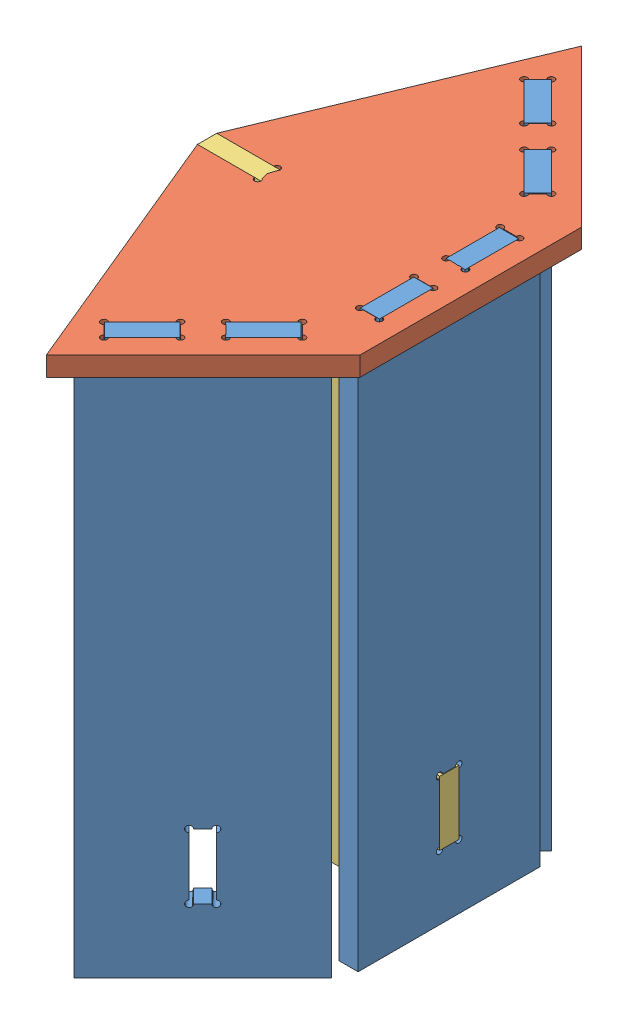
SolidWorks assembly ChairASSLY, configuration Default. Lengths in mm.
Overall size (246.27 518 500).
5 component instances, 3 part files, 13 mates.
Components (placement in the parent):
- Part1-1: Part1 [Default] at (991.7789 -819.0131 -319.6373) size (18 518 170)
- Part5-1: Part5 [Default] at (12065.9695 -301.0131 1743.1464) size (246.27 18 500)
- Part1-2: Part1 [Default] at (869.4047 -819.0131 -194.6999) x (0.707107 0 0.707107) z (-0.707107 0 0.707107) size (18 518 170)
- Part1-3: Part1 [Default] at (989.6128 -819.0131 -494.8667) x (0.707107 0 -0.707107) z (0.707107 0 0.707107) size (18 518 170)
- Stiffener-1: Stiffener [Default] at (-1537.8643 -62.9023 94.9374) size (226.27 518 18)
Mates (geometry in assembly coordinates):
- Width2: width aligned: plane of Part5-1 through (919.0789 -319.0131 -244.3741) normal (-0.707107 0 0.707107); plane of Part5-1 through (883.37 -319.0131 -208.6652) normal (0.707107 0 -0.707107); plane of Part1-2 through (883.5468 -301.0131 -208.842) normal (-0.707107 0 0.707107); plane of Part1-2 through (918.9022 -301.0131 -244.1973) normal (0.707107 0 -0.707107)
- Width3: width aligned: plane of Part1-2 through (882.1326 -819.0131 -181.9719) normal (0.707107 0 0.707107); plane of Part1-2 through (869.4047 -819.0131 -194.6999) normal (-0.707107 0 -0.707107); plane of Part5-1 through (976.001 -319.0131 -301.2962) normal (0.707107 0 0.707107); plane of Part5-1 through (988.729 -319.0131 -288.5683) normal (-0.707107 0 -0.707107)
- Width4: width anti-aligned: plane of Part5-1 through (919.0789 -319.0131 -244.3741) normal (-0.707107 0 0.707107); plane of Part5-1 through (883.37 -319.0131 -208.6652) normal (0.707107 0 -0.707107); plane of Part1-2 through (918.9022 -301.0131 -244.1973) normal (0.707107 0 -0.707107); plane of Part1-2 through (883.5468 -301.0131 -208.842) normal (-0.707107 0 0.707107)
- Coincident16: coincident anti-aligned: plane of Part5-1 through (12065.9695 -319.0131 1743.1464) normal (0 -1 0); plane of Part1-2 through (1002.3408 -319.0131 -302.1801) normal (0 1 0)
- Width5: width anti-aligned: plane of Part5-1 through (991.7789 -319.0131 -339.3873) normal (0 0 -1); plane of Part5-1 through (991.7789 -319.0131 -389.8873) normal (0 0 1); plane of Part1-1 through (991.7789 -301.0131 -339.6373) normal (0 0 1); plane of Part1-1 through (991.7789 -301.0131 -389.6373) normal (0 0 -1)
- Coincident17: coincident anti-aligned: plane of Part1-1 through (1009.7789 -319.0131 -489.6373) normal (0 1 0); plane of Part5-1 through (12065.9695 -319.0131 1743.1464) normal (0 -1 0)
- Width6: width anti-aligned: plane of Part5-1 through (991.7789 -319.0131 -339.3873) normal (1 0 0); plane of Part5-1 through (1009.7789 -319.0131 -339.3873) normal (-1 0 0); plane of Part1-1 through (991.7789 -819.0131 -319.6373) normal (-1 0 0); plane of Part1-1 through (1009.7789 -819.0131 -319.6373) normal (1 0 0)
- Width7: width aligned: plane of Part5-1 through (976.001 -319.0131 -508.4785) normal (0.707107 0 -0.707107); plane of Part5-1 through (988.729 -319.0131 -521.2064) normal (-0.707107 0 0.707107); plane of Part1-3 through (1002.3408 -819.0131 -507.5946) normal (0.707107 0 -0.707107); plane of Part1-3 through (989.6128 -819.0131 -494.8667) normal (-0.707107 0 0.707107)
- Width8: width anti-aligned: plane of Part5-1 through (883.37 -319.0131 -601.1095) normal (0.707107 0 0.707107); plane of Part5-1 through (919.0789 -319.0131 -565.4006) normal (-0.707107 0 -0.707107); plane of Part1-3 through (883.5468 -301.0131 -600.9327) normal (-0.707107 0 -0.707107); plane of Part1-3 through (918.9022 -301.0131 -565.5774) normal (0.707107 0 0.707107)
- Coincident18: coincident anti-aligned: plane of Part5-1 through (12065.9695 -319.0131 1743.1464) normal (0 -1 0); plane of Part1-3 through (882.1326 -319.0131 -627.8028) normal (0 1 0)
- Width9: width anti-aligned: plane of Stiffener-1 through (-1537.8643 -62.9023 -413.8873) normal (0 0 -1); plane of Stiffener-1 through (-1537.8643 -62.9023 -395.8873) normal (0 0 1); plane of Part5-1 through (783.5068 398.1203 -413.8873) normal (0 0 1); plane of Part5-1 through (783.5068 398.1203 -395.8873) normal (0 0 -1)
- Symmetric1: symmetric anti-aligned: plane of Part5-1 through (839.7789 398.1203 -413.8873) normal (-1 0 0); plane of Stiffener-1 through (843.5068 -301.0131 -413.8873) normal (1 0 0); plane of Stiffener-1 through (-1537.8643 -62.9023 -413.8873) normal (0 0 -1)
- Coincident20: coincident aligned: plane of Part5-1 through (12065.9695 -301.0131 1743.1464) normal (0 1 0); plane of Stiffener-1 through (-1537.8643 -301.0131 94.9374) normal (0 1 0)
